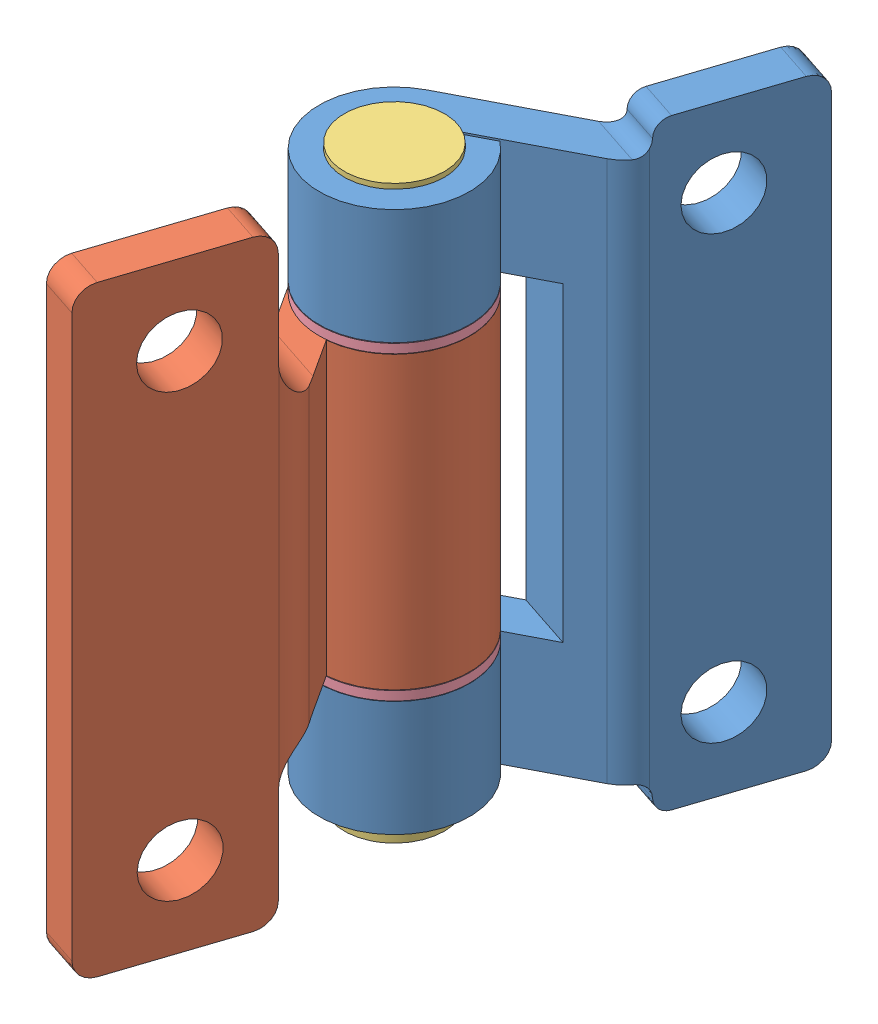
SolidWorks assembly Yaprak Menteşe 1599, configuration Varsayılan. Lengths in mm.
Overall size (34.49 60 62.15).
5 component instances, 4 part files, 8 mates.
Components (placement in the parent):
- M1-1: M1 [Varsayılan] at (8.2301 -34.386 65.7249) x (-0.313667 0 0.949533) z (-0.949533 0 -0.313667) size (37.5 60 16.5)
- M2-1: M2 [Varsayılan] at (8.2301 -34.386 65.7249) x (-0.313667 0 0.949533) z (-0.949533 0 -0.313667) size (37.5 60 16.5)
- M3-1: M3 [Varsayılan] at (8.2301 -33.886 65.7249) x (0.861192 0 -0.50828) z (0.50828 0 0.861192) size (10 57 10)
- M4-1: M4 [Varsayılan] at (8.2301 10.164 65.7249) x (0.996562 0 0.082856) z (-0.082856 0 0.996562) size (15 0.9 15)
- M4-2: M4 [Varsayılan] at (8.2301 -19.836 65.7249) x (0.996562 0 0.082856) z (-0.082856 0 0.996562) size (15 0.9 15)
Mates (geometry in assembly coordinates):
- Eş Merkezli1: concentric aligned: cylinder of M1-1 through (8.2301 25.614 65.7249) axis (0 -1 0) radius 5; cylinder of M2-1 through (8.2301 25.614 65.7249) axis (0 -1 0) radius 5
- Genişlik1: width anti-aligned: plane of M1-1 through (63.7479 11.114 73.0065) normal (0 -1 0); plane of M2-1 through (63.7479 -19.886 73.0065) normal (0 1 0); plane of M1-1 through (37.1665 10.114 89.7118) normal (0 1 0); plane of M2-1 through (37.1665 -18.886 89.7118) normal (0 -1 0)
- Eş Merkezli2: concentric aligned: cylinder of M1-1 through (8.2301 25.614 65.7249) axis (0 -1 0) radius 5; cylinder of M3-1 through (8.2301 23.114 65.7249) axis (0 -1 0) radius 5
- Uzaklık2: distance = 0.5 mm aligned: plane of M3-1 through (8.2301 23.114 65.7249) normal (0 1 0); plane of M1-1 through (8.2301 22.614 65.7249) normal (0 1 0)
- Eş Merkezli3: concentric aligned: cylinder of M3-1 through (8.2301 23.114 65.7249) axis (0 -1 0) radius 5; cylinder of M4-1 through (8.2301 11.064 65.7249) axis (0 -1 0) radius 5
- Genişlik2: width anti-aligned: plane of M1-1 through (63.7479 11.114 73.0065) normal (0 -1 0); plane of M2-1 through (37.1665 10.114 89.7118) normal (0 1 0); plane of M4-1 through (8.2301 11.064 65.7249) normal (0 1 0); plane of M4-1 through (8.2301 10.164 65.7249) normal (0 -1 0)
- Genişlik3: width anti-aligned: plane of M2-1 through (37.1665 -18.886 89.7118) normal (0 -1 0); plane of M4-2 through (63.7479 -19.886 73.0065) normal (0 1 0); plane of M1-1 through (8.2301 -18.936 65.7249) normal (0 1 0); plane of M4-2 through (8.2301 -19.836 65.7249) normal (0 -1 0)
- Eş Merkezli4: concentric anti-aligned: cylinder of M2-1 through (8.2301 25.614 65.7249) axis (0 -1 0) radius 7.5; circle of M4-2
